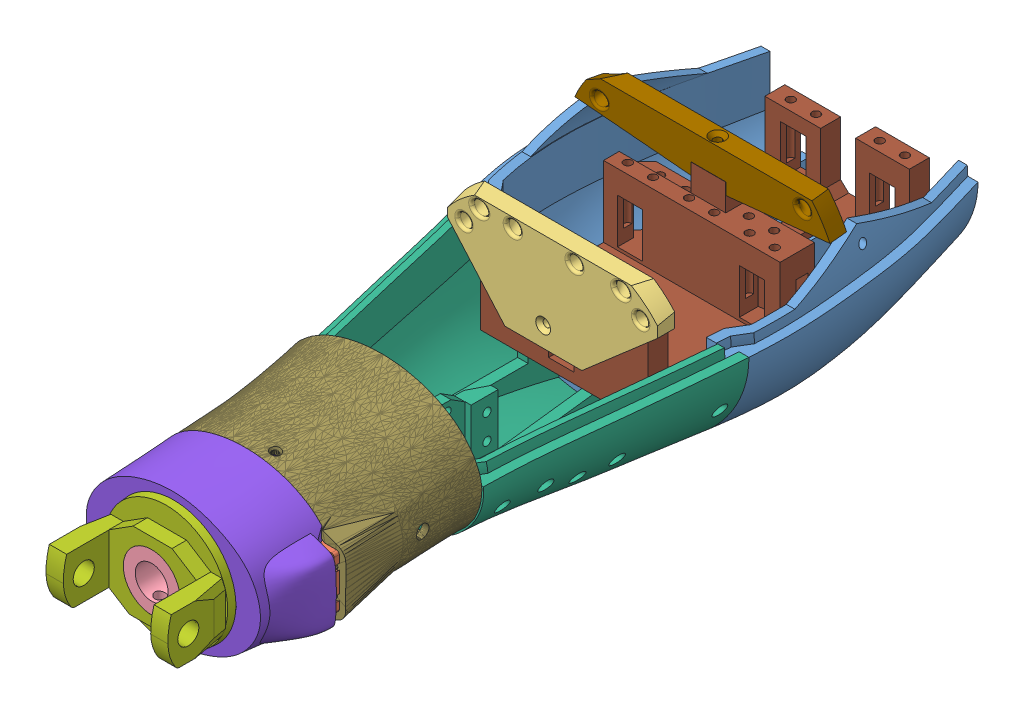
SolidWorks assembly Forearm_R_complete01, configuration Default. Lengths in mm.
Overall size (116.46 75.21 303.56).
17 component instances, 17 part files, 2 mates.
Components (placement in the parent):
- RobCap3-1: RobCap3 [Default] at origin size (91.43 83.2 17.08) (hidden)
- RobPart5-1: RobPart5 [Default] at origin size (115.81 64.39 109.17)
- Standard Servo-1: Standard Servo [Default] at origin size (52.1 20 39.84)
- RobCableFront-1: RobCableFront [Default] at origin size (81.34 38.24 14.1)
- ElbowShaftGear-1: ElbowShaftGear [Default] at origin size (58.16 67.94 26.1) (hidden)
- WristGear1-1: WristGear1 [Default] at origin size (28.99 28.99 17)
- WristGear2-1: WristGear2 [Default] at origin size (16.38 16.49 8.5)
- RobPart2-1: RobPart2 [Default] at origin size (115.62 55.99 98.77)
- RotaWrist3-1: RotaWrist3 [Default] at origin size (49.74 48.21 25.56)
- RotaWrist2-1: RotaWrist2 [Default] at origin size (76.87 55.51 39.33)
- RobPart3-1: RobPart3 [Default] at origin size (111.26 48.27 99.49) (hidden)
- RobPart4-1: RobPart4 [Default] at origin size (113.24 51.4 107.58) (hidden)
- RotaWrist1-1: RotaWrist1 [Default] at origin size (83.81 59 55.86) (hidden)
- RobCableBack-1: RobCableBack [Default] at origin size (96.46 15.96 7.25)
- CableHolderWrist-1: CableHolderWrist [Default] at origin size (20.21 33.16 6.45)
- RobServoBed-1: RobServoBed [Default] at origin size (66.72 39.63 111.57)
- Rotawrist1V4-1: Rotawrist1V4 [Default] at (13.6554 -5.2682 92.5) x (-0.999959 0.009047 0) z (0 0 1) size (78.57 52.81 54.52)
Mates (geometry in assembly coordinates):
- Coincident1: coincident anti-aligned: plane of RobPart2-1 through (0 0 92.5) normal (0 0 1); plane of Rotawrist1V4-1 through (13.6554 -5.2682 92.5) normal (0 0 -1)
- Concentric2: concentric anti-aligned: circle of Standard Servo-1; circle of Rotawrist1V4-1
